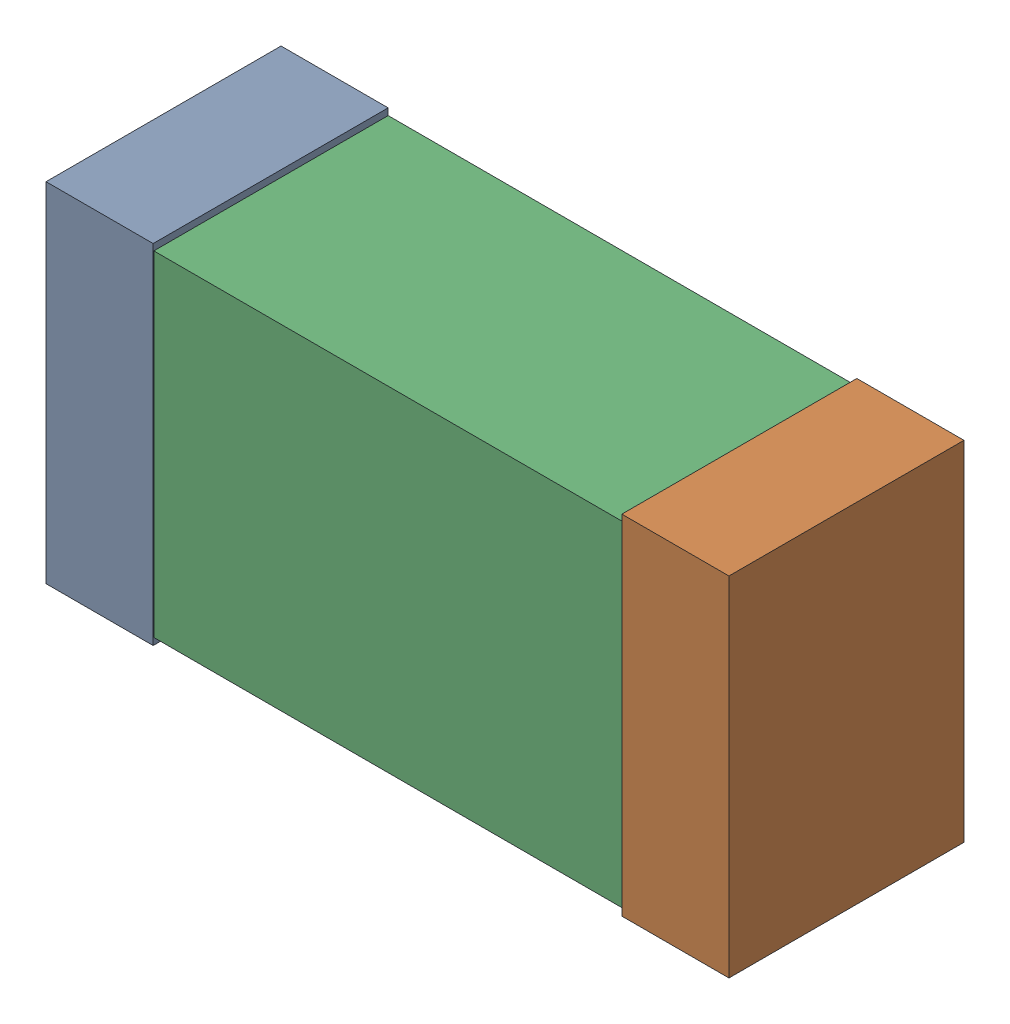
SolidWorks assembly C42, configuration Default. Lengths in mm.
Overall size (1.02 0.52 0.35).
6 component instances, 2 part files, 0 mates.
Components (placement in the parent):
- 870940480-1: 870940480 [Default] at (76.455 44.016 0) size (0.16 0.52 0.35)
  - Extruded-1: Extruded [Default] at origin size (0.16 0.52 0.35)
- 870940480-2: 870940480 [Default] at (77.315 44.016 0) size (0.16 0.52 0.35)
  - Extruded-1: Extruded [Default] at origin size (0.16 0.52 0.35)
- 870940640-1: 870940640 [Default] at (76.885 44.016 0) size (1 0.5 0.35)
  - Extruded_2-1: Extruded_2 [Default] at origin size (1 0.5 0.35)
